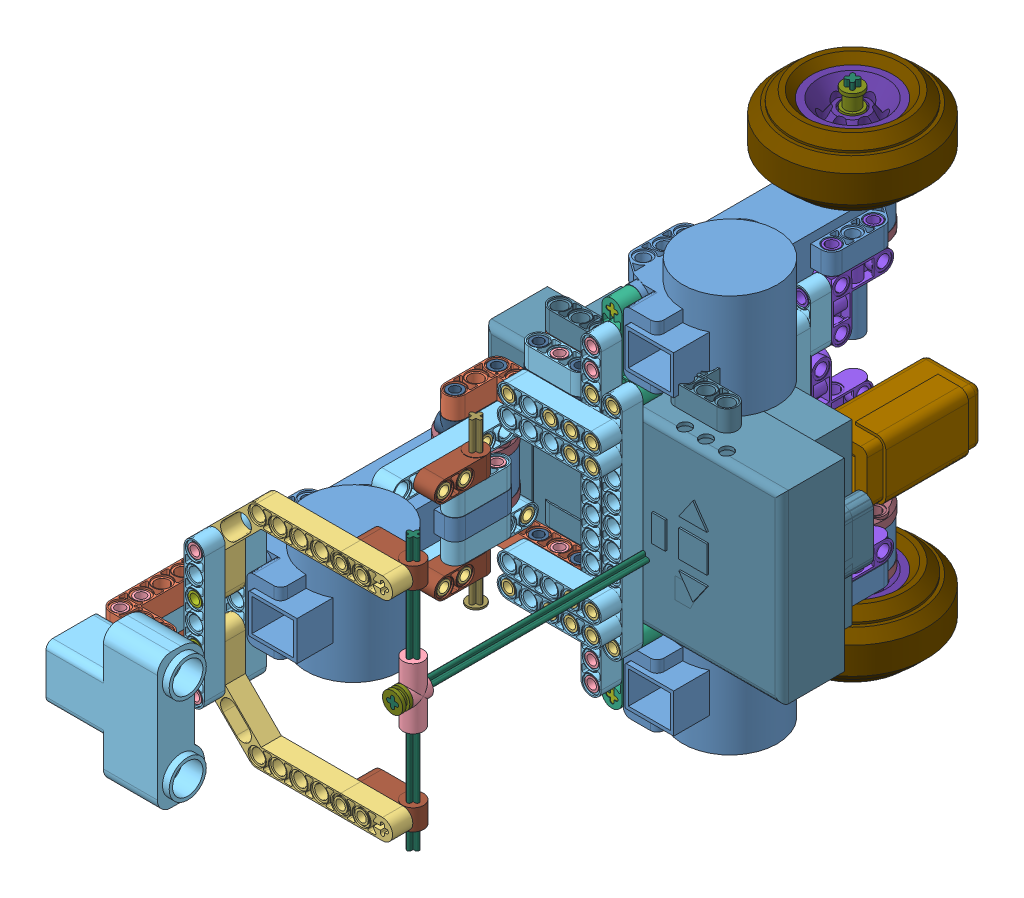
SolidWorks assembly ETRobocon2013_import, configuration Default. Lengths in mm.
Overall size (189.46 186.94 314.84).
140 component instances, 23 part files, 8 mates.
Components (placement in the parent):
- NXT+^ETRobocon2013_import-1: NXT+^ETRobocon2013_import [Default] at (300.3789 -80.9933 -218.1999) x (1 0 0) z (0 0 1) size (114.94 149.61 157.1) (virtual)
  - Motor-1: Motor [Default] at (-38.073 -89.9097 15.5114) x (0 0 1) z (1 0 0) size (103.9 39.37 46.48)
  - Motor-2: Motor [Default] at (-38.073 20.3263 15.5114) x (0 0 1) z (1 0 0) size (103.9 39.37 46.48)
  - left_connector-1: left_connector [Default] at (-38.073 -66.5417 23.3854) x (0 1 0) z (1 0 0) size (23.11 39.12 23.37)
    - L_Three_Five_90degrees-1: L_Three_Five_90degrees [Default] x (0 1 0) z (-1 0 0) size (39.12 23.37 7.87)
    - BlackConnectorSmall-1: BlackConnectorSmall [Default] at (-7.366 7.874 0) size (15.24 5.59 5.59)
    - BlackConnectorSmall-2: BlackConnectorSmall [Default] at (-15.24 -23.622 0) size (15.24 5.59 5.59)
    - BlueConnectorLong-1: BlueConnectorLong [Default] at (-15.24 -7.874 0) size (22.86 5.59 5.59)
  - right_connector-1: right_connector [Default] at (-38.073 12.1983 23.3854) x (0 1 0) z (1 0 0) size (23.11 39.12 23.37)
    - L_Three_Five_90degrees-1: L_Three_Five_90degrees [Default] x (0 1 0) z (-1 0 0) size (39.12 23.37 7.87)
    - BlackConnectorSmall-1: BlackConnectorSmall [Default] at (0 7.874 0) x (-1 0 0) z (0 0 -1) size (15.24 5.59 5.59)
    - BlackConnectorSmall-2: BlackConnectorSmall [Default] at (7.874 -23.622 0) x (-1 0 0) z (0 0 -1) size (15.24 5.59 5.59)
    - BlueConnectorLong-1: BlueConnectorLong [Default] at (7.874 -7.874 0) x (-1 0 0) z (0 0 -1) size (22.86 5.59 5.59)
  - horizontal_connector-1: horizontal_connector [Default] at (-22.325 -30.8547 35.1964) x (0 1 0) z (1 0 0) size (133.6 31.24 39.12)
    - All_Straight-1: All_Straight [Eleven] at (31.496 0 0) x (1 0 0) z (0 1 0) size (86.36 7.62 7.87)
    - BlackConnectorSmall-1: BlackConnectorSmall [Default] at (39.37 7.62 0) x (0 -1 0) z (0 0 1) size (15.24 5.59 5.59)
    - BlackConnectorSmall-2: BlackConnectorSmall [Default] at (-39.37 7.62 0) x (0 -1 0) z (0 0 1) size (15.24 5.59 5.59)
    - BlackConnectorSmall-4: BlackConnectorSmall [Default] at (-23.622 0.254 0) x (0 1 0) z (0 0 -1) size (15.24 5.59 5.59)
    - BlackConnectorSmall-5: BlackConnectorSmall [Default] at (23.622 0.254 0) x (0 1 0) z (0 0 -1) size (15.24 5.59 5.59)
    - L_Two_Four_90degrees-1: L_Two_Four_90degrees [Default] at (47.4776 -6.6697 -16.0899) x (1 0 0) z (0 -1 0) size (31.24 15.49 7.87)
    - L_Two_Four_90degrees-3: L_Two_Four_90degrees [Default] at (-47.4776 -1.2043 -16.0899) x (-1 0 0) z (0 1 0) size (31.24 15.49 7.87)
    - BlackConnectorSmall-6: BlackConnectorSmall [Default] at (-39.37 -7.62 -7.874) x (0 1 0) z (0 0 -1) size (15.24 5.59 5.59)
    - BlackConnectorSmall-7: BlackConnectorSmall [Default] at (39.37 -7.62 -7.874) x (0 1 0) z (0 0 -1) size (15.24 5.59 5.59)
    - BlueConnectorLong-1: BlueConnectorLong [Default] at (47.244 7.62 -7.874) x (0 -1 0) z (-1 0 0) size (22.86 5.59 5.59)
    - BlueConnectorLong-2: BlueConnectorLong [Default] at (55.118 7.62 -7.874) x (0 -1 0) z (-1 0 0) size (22.86 5.59 5.59)
    - BlueConnectorLong-3: BlueConnectorLong [Default] at (-47.244 7.62 -7.874) x (0 -1 0) z (0 0 1) size (22.86 5.59 5.59)
    - BlueConnectorLong-4: BlueConnectorLong [Default] at (-55.118 7.62 -7.874) x (0 -1 0) z (0 0 1) size (22.86 5.59 5.59)
    - All_Straight-3: All_Straight [Fifteen] at (47.244 0 -7.874) x (1 0 0) z (0 1 0) size (117.86 7.62 7.87)
    - BlackConnectorSmall-8: BlackConnectorSmall [Default] at (23.622 0.254 -7.874) x (0 1 0) z (0 0 -1) size (15.24 5.59 5.59)
    - BlackConnectorSmall-9: BlackConnectorSmall [Default] at (-23.622 0.254 -7.874) x (0 1 0) z (0 0 -1) size (15.24 5.59 5.59)
    - All_Straight-4: All_Straight [Five] at (-23.622 15.748 -7.874) x (0 0 1) z (0 -1 0) size (39.12 7.62 7.87)
    - All_Straight-5: All_Straight [Five] at (23.622 15.748 -7.874) x (0 0 1) z (0 -1 0) size (39.12 7.62 7.87)
    - BlueConnectorCross_Tube-1: BlueConnectorCross_Tube [Default] at (62.992 -7.874 -7.874) x (0 -1 0) z (0 0 1) size (15.24 5.08 5.08)
    - BlueConnectorCross_Tube-2: BlueConnectorCross_Tube [Default] at (-62.992 -7.874 -7.874) x (0 -1 0) z (0 0 -1) size (15.24 5.08 5.08)
  - lower_horizontal_connector-1: lower_horizontal_connector [Default] at (-14.451 0.6413 -19.9216) x (0 1 0) z (1 0 0) size (117.86 51.45 29.62)
    - All_Straight-1: All_Straight [Eleven] x (1 0 0) z (0 1 0) size (86.36 7.62 7.87)
    - BlueConnectorLong-1: BlueConnectorLong [Default] at (7.874 7.493 0) x (0 -1 0) z (0 0 1) size (22.86 5.59 5.59)
    - BlueConnectorLong-2: BlueConnectorLong [Default] at (-70.866 7.493 0) x (0 -1 0) z (0 0 1) size (22.86 5.59 5.59)
    - All_Straight-2: All_Straight [Three] at (7.874 -8.001 0) x (1 0 0) z (0 1 0) size (23.37 7.62 7.87)
    - All_Straight-3: All_Straight [Three] at (-70.866 -8.001 0) x (1 0 0) z (0 1 0) size (23.37 7.62 7.87)
    - Light_Gray_X10-1: Light_Gray_X10 [Default] at (-70.866 -15.621 0) size (31.24 31.24 7.62)
    - Light_Gray_X10-3: Light_Gray_X10 [Default] at (7.874 -15.621 0) x (-1 0 0) z (0 0 -1) size (31.24 31.24 7.62)
    - Light_Gray_X10-4: Light_Gray_X10 [Default] at (-15.748 -8.001 0) size (31.24 31.24 7.62)
    - Light_sensor-1: Light_sensor [Default] at (-31.904 -21.981 14.31) x (-1 0 0) z (0 -1 0) size (22.5 29.62 43.2)
  - left_rider_bottom-1: left_rider_bottom [Default] at (-65.632 -46.6027 78.5034) x (0 1 0) z (1 0 0) size (39.12 54.99 54.99)
    - All_Straight-1: All_Straight [Seven] x (0 1 0) z (0 0 1) size (54.86 7.62 7.87)
    - BlackConnectorSmall-1: BlackConnectorSmall [Default] at (0 0 15.494) x (0 0 -1) z (1 0 0) size (15.24 5.59 5.59)
    - BlackConnectorSmall-3: BlackConnectorSmall [Default] at (0 -7.874 15.494) x (0 0 -1) z (1 0 0) size (15.24 5.59 5.59)
    - BlackConnectorSmall-4: BlackConnectorSmall [Default] at (0 -23.622 -7.62) x (0 0 1) z (1 0 0) size (15.24 5.59 5.59)
    - BlackConnectorSmall-5: BlackConnectorSmall [Default] at (0 -39.37 -7.62) x (0 0 1) z (1 0 0) size (15.24 5.59 5.59)
    - Light_Gray_X1-1: Light_Gray_X1 [Default] at (3.937 -31.496 -3.937) x (0 1 0) z (0 0 1) size (23.62 23.11 7.87)
    - StraightTurn_Twohole_1Cross-1: StraightTurn_Twohole_1Cross [Default] at (3.81 -7.747 11.811) x (0 -1 0) z (-1 0 0) size (23.5 7.87 7.87)
    - L_Three_Five_90degrees-1: L_Three_Five_90degrees [Default] at (-11.557 -39.37 3.937) x (0 0 -1) z (1 0 0) size (39.12 23.37 7.87)
    - Light_Gray_X1-2: Light_Gray_X1 [Default] at (-19.685 -39.37 19.685) x (0 0 -1) z (0 -1 0) size (23.62 23.11 7.87)
    - BlueConnectorLong-1: BlueConnectorLong [Default] at (-27.305 -39.37 19.685) size (22.86 5.59 5.59)
    - BlackConnectorSmall-6: BlackConnectorSmall [Default] at (-15.748 -27.813 11.811) x (0 -1 0) z (0 0 1) size (15.24 5.59 5.59)
    - BlackConnectorSmall-7: BlackConnectorSmall [Default] at (-15.748 -27.813 27.559) x (0 -1 0) z (0 0 1) size (15.24 5.59 5.59)
    - All_Straight-2: All_Straight [Five] at (-15.748 -35.433 19.685) x (0 0 -1) z (0 1 0) size (39.12 7.62 7.87)
    - All_Straight-3: All_Straight [Three] at (-27.559 -39.37 19.685) x (0 0 -1) z (1 0 0) size (23.37 7.62 7.87)
    - BlackConnectorSmall-8: BlackConnectorSmall [Default] at (-15.748 -43.053 35.433) x (0 1 0) z (0 0 1) size (15.24 5.59 5.59)
    - BlackConnectorSmall-9: BlackConnectorSmall [Default] at (-15.748 -43.053 43.307) x (0 1 0) z (1 0 0) size (15.24 5.59 5.59)
  - right_rider_bottom-1: right_rider_bottom [Default] at (-65.632 -15.1067 78.5034) x (0 1 0) z (1 0 0) size (39.12 54.99 54.99)
    - All_Straight-1: All_Straight [Seven] x (0 1 0) z (0 0 1) size (54.86 7.62 7.87)
    - BlackConnectorSmall-1: BlackConnectorSmall [Default] at (0 0 15.494) x (0 0 -1) z (1 0 0) size (15.24 5.59 5.59)
    - BlackConnectorSmall-3: BlackConnectorSmall [Default] at (0 -7.874 15.494) x (0 0 -1) z (1 0 0) size (15.24 5.59 5.59)
    - BlackConnectorSmall-4: BlackConnectorSmall [Default] at (0 -23.622 -7.62) x (0 0 1) z (1 0 0) size (15.24 5.59 5.59)
    - BlackConnectorSmall-5: BlackConnectorSmall [Default] at (0 -39.37 -7.62) x (0 0 1) z (1 0 0) size (15.24 5.59 5.59)
    - Light_Gray_X1-1: Light_Gray_X1 [Default] at (3.937 -31.496 -3.937) x (0 1 0) z (0 0 1) size (23.62 23.11 7.87)
    - StraightTurn_Twohole_1Cross-1: StraightTurn_Twohole_1Cross [Default] at (3.81 -7.747 11.811) x (0 -1 0) z (-1 0 0) size (23.5 7.87 7.87)
    - L_Three_Five_90degrees-1: L_Three_Five_90degrees [Default] at (4.191 -39.37 3.937) x (0 0 -1) z (1 0 0) size (39.12 23.37 7.87)
    - Light_Gray_X1-2: Light_Gray_X1 [Default] at (19.685 -39.37 19.685) x (0 0 -1) z (0 1 0) size (23.62 23.11 7.87)
    - BlueConnectorLong-1: BlueConnectorLong [Default] at (27.305 -39.37 19.685) x (-1 0 0) z (0 0 -1) size (22.86 5.59 5.59)
    - BlackConnectorSmall-6: BlackConnectorSmall [Default] at (15.748 -27.813 11.811) x (0 -1 0) z (0 0 1) size (15.24 5.59 5.59)
    - BlackConnectorSmall-7: BlackConnectorSmall [Default] at (15.748 -27.813 27.559) x (0 -1 0) z (0 0 1) size (15.24 5.59 5.59)
    - All_Straight-2: All_Straight [Five] at (15.748 -35.433 19.685) x (0 0 -1) z (0 1 0) size (39.12 7.62 7.87)
    - All_Straight-3: All_Straight [Three] at (27.559 -39.37 19.685) x (0 0 -1) z (-1 0 0) size (23.37 7.62 7.87)
    - BlackConnectorSmall-8: BlackConnectorSmall [Default] at (15.748 -27.813 43.307) x (0 -1 0) z (0 0 1) size (15.24 5.59 5.59)
    - BlackConnectorSmall-9: BlackConnectorSmall [Default] at (15.748 -27.813 35.433) x (0 -1 0) z (0 0 1) size (15.24 5.59 5.59)
  - CrossTemplateWithCap-1: CrossTemplateWithCap [Eight] at (-53.821 -61.3347 64.2794) x (0 0 -1) z (0 1 0) size (6.6 6.6 60.96)
  - Rotor-1: Rotor [Default] at (-69.569 -23.6157 47.0074) x (0 0 -1) z (0 1 0) size (23.62 23.62 23.66)
  - CPU-1: CPU [Default] at (0 15.748 0) size (111.76 85.98 40)
- WheelLeft^ETRobocon2013_import-1: WheelLeft^ETRobocon2013_import [Default] at (270.1799 -49.491 -273.5545) x (-0.695581 0 -0.718448) z (0 1 0) size (55.88 55.88 82.68) (virtual)
  - Rotor-1: Rotor [Default] at origin size (23.62 23.62 23.66)
  - wheel_and_axle-1: wheel_and_axle [Default] at (-1.524 0 31.115) x (0 0 -1) z (-1 0 0) size (82.68 55.88 55.88)
    - CrossTemplate-1: CrossTemplate [Nine] x (0 0 -1) z (1 0 0) size (4.57 4.57 70.87)
    - Light_Gray_X8__Template-1: Light_Gray_X8__Template [one] at (2.54 0 6.35) x (0 0 -1) z (1 0 0) size (7.62 7.62 7.87)
    - Light_Gray_X12-1: Light_Gray_X12 [Rim] at (16.637 0 -9.144) x (0 0 1) z (-1 0 0) size (30.48 30.48 20.07)
    - Light_Gray_X13-1: Light_Gray_X13 [Tire] at (16.637 0 6.096) x (0 0 -1) z (1 0 0) size (55.88 55.88 25.4)
    - Light_Gray_X8__Template-2: Light_Gray_X8__Template [half] at (22.86 0 6.35) x (0 0 -1) z (1 0 0) size (7.62 7.62 3.94)
    - CrossComplementEnd_Small-1: CrossComplementEnd_Small [Three] at (59.054 0 0) x (0 0 -1) z (1 0 0) size (7.62 7.62 23.62)
- WheelRight^ETRobocon2013_import-1: WheelRight^ETRobocon2013_import [Default] at (270.1799 -159.727 -273.5545) x (-0.059852 0 -0.998207) z (0 1 0) size (55.88 55.88 82.68) (virtual)
  - Rotor-1: Rotor [Default] at origin size (23.62 23.62 23.66)
  - wheel_and_axle-1: wheel_and_axle [Default] at (-1.524 0 -45.593) x (0 0 1) z (-1 0 0) size (82.68 55.88 55.88)
    - CrossTemplate-1: CrossTemplate [Nine] x (0 0 -1) z (1 0 0) size (4.57 4.57 70.87)
    - Light_Gray_X8__Template-1: Light_Gray_X8__Template [one] at (2.54 0 6.35) x (0 0 -1) z (1 0 0) size (7.62 7.62 7.87)
    - Light_Gray_X12-1: Light_Gray_X12 [Rim] at (16.637 0 -9.144) x (0 0 1) z (-1 0 0) size (30.48 30.48 20.07)
    - Light_Gray_X13-1: Light_Gray_X13 [Tire] at (16.637 0 6.096) x (0 0 -1) z (1 0 0) size (55.88 55.88 25.4)
    - Light_Gray_X8__Template-2: Light_Gray_X8__Template [half] at (22.86 0 6.35) x (0 0 -1) z (1 0 0) size (7.62 7.62 3.94)
    - CrossComplementEnd_Small-1: CrossComplementEnd_Small [Three] at (59.054 0 0) x (0 0 -1) z (1 0 0) size (7.62 7.62 23.62)
- Humanoid^ETRobocon2013_import-1: Humanoid^ETRobocon2013_import [Default] at (213.4588 -175.874 209.2441) x (0.467807 0 -0.883831) z (0.883831 0 0.467807) size (169.56 102.11 124.61) (virtual)
  - Motor-1: Motor [Default] at (278.0414 60.089 -136.4432) x (-0.883831 0 0.467807) z (0.467807 0 0.883831) size (103.9 39.37 46.48)
  - All_Straight-1: All_Straight [Three] at (337.807 52.215 -141.3499) x (0.883831 0 -0.467807) z (0 1 0) size (23.37 7.62 7.87)
  - BlueConnectorLong-1: BlueConnectorLong [Default] at (330.8477 52.469 -137.6664) x (0 1 0) z (0 0 1) size (22.86 5.59 5.59)
  - BlueConnectorLong-2: BlueConnectorLong [Default] at (344.7662 75.583 -145.0334) x (0 -1 0) z (-0.122872 0 0.992423) size (22.86 5.59 5.59)
  - All_Straight-2: All_Straight [Three] at (337.807 67.963 -141.3499) x (-0.883831 0 0.467807) z (0 1 0) size (23.37 7.62 7.87)
  - CrossConnectorLong-1: CrossConnectorLong [Default] at (271.9809 44.341 -131.4163) x (0.769691 0 -0.638416) z (0 1 0) size (7.62 7.62 23.62)
  - CrossConnectorLong-2: CrossConnectorLong [Default] at (285.8995 44.341 -138.7833) x (0.769691 0 -0.638416) z (0 1 0) size (7.62 7.62 23.62)
  - arms_and_chest-1: arms_and_chest [Default] at (250.6327 79.774 -113.0269) x (0 1 0) z (0.467807 0 0.883831) size (102.11 106.17 70.74)
    - All_Straight-1: All_Straight [Seven] x (1 0 0) z (0 -1 0) size (54.86 7.62 7.87)
    - BlueConnectorLong-1: BlueConnectorLong [Default] at (-39.37 -0.254 0) x (0 -1 0) z (0 0 1) size (22.86 5.59 5.59)
    - BlueConnectorLong-3: BlueConnectorLong [Default] at (7.874 -0.254 0) x (0 -1 0) z (0 0 1) size (22.86 5.59 5.59)
    - BlueConnectorCross_Tube-1: BlueConnectorCross_Tube [Default] at (-23.622 -7.874 0) x (0 1 0) z (0 0 1) size (15.24 5.08 5.08)
    - BlueConnectorCross_Tube-2: BlueConnectorCross_Tube [Default] at (-7.874 -7.874 0) x (0 1 0) z (0 0 1) size (15.24 5.08 5.08)
    - Three_Four_Seven_90degreesTurn-1: Three_Four_Seven_90degreesTurn [Default] at (-31.496 -15.494 0) x (1 0 0) z (0 1 0) size (39.12 70.61 7.62)
    - Three_Four_Seven_90degreesTurn-4: Three_Four_Seven_90degreesTurn [Default] at (0 -7.874 0) x (-1 0 0) z (0 -1 0) size (39.12 70.61 7.62)
    - All_Straight-2: All_Straight [Seven] at (0 -23.368 0) x (1 0 0) z (0 1 0) size (54.86 7.62 7.87)
    - BlackConnectorSmall-1: BlackConnectorSmall [Default] at (23.622 -7.874 47.244) x (0 -1 0) z (0 0 1) size (15.24 5.59 5.59)
    - BlackConnectorSmall-2: BlackConnectorSmall [Default] at (23.622 -7.874 55.118) x (0 -1 0) z (0 0 1) size (15.24 5.59 5.59)
    - BlackConnectorSmall-3: BlackConnectorSmall [Default] at (-55.118 -7.874 47.244) x (0 -1 0) z (0 0 1) size (15.24 5.59 5.59)
    - BlackConnectorSmall-4: BlackConnectorSmall [Default] at (-55.118 -7.874 55.118) x (0 -1 0) z (0 0 1) size (15.24 5.59 5.59)
    - BlackConnectorSmall-5: BlackConnectorSmall [Default] at (-31.496 -23.114 0) x (0 1 0) z (0 0 1) size (15.24 5.59 5.59)
    - BlackConnectorSmall-6: BlackConnectorSmall [Default] at (0 -23.114 0) x (0 1 0) z (0 0 1) size (15.24 5.59 5.59)
    - StraightTurn_Twohole_1Cross-1: StraightTurn_Twohole_1Cross [Default] at (27.432 -19.431 54.991) x (0 0 1) z (-1 0 0) size (23.5 7.87 7.87)
    - StraightTurn_Twohole_1Cross-2: StraightTurn_Twohole_1Cross [Default] at (-51.308 -19.431 54.991) x (0 0 1) z (-1 0 0) size (23.5 7.87 7.87)
    - CrossTemplate-1: CrossTemplate [Six] at (-11.938 -19.431 64.516) x (0 0 -1) z (1 0 0) size (4.57 4.57 47.24)
    - Cross_AngleHole-1: Cross_AngleHole [Default] at (-4.318 -19.431 61.468) x (0 0 1) z (-1 0 0) size (7.62 7.62 22.86)
    - CrossTemplate-2: CrossTemplate [Six] at (-66.802 -19.431 64.516) x (0 0 -1) z (1 0 0) size (4.57 4.57 47.24)
    - CrossTemplate-3: CrossTemplate [Twelve] at (-17.272 -11.684 62.992) x (1 0 0) z (0 -1 0) size (4.57 4.57 94.49)
    - Light_Gray_X8__Template-1: Light_Gray_X8__Template [half] at (-23.622 -11.684 62.992) x (1 0 0) z (0 -1 0) size (7.62 7.62 3.94)
    - BlackConnectorSmall-7: BlackConnectorSmall [Default] at (-7.874 -15.748 0) x (0 -1 0) z (0 0 1) size (15.24 5.59 5.59)
    - BlackConnectorSmall-8: BlackConnectorSmall [Default] at (-23.622 -15.748 0) x (0 -1 0) z (0 0 1) size (15.24 5.59 5.59)
  - head-1: head [Default] at (237.5152 63.2753 -95.1876) x (0.467807 0 0.883831) z (0 -1 0) size (44.45 98.81 50.8)
    - ProximitySensor-1: ProximitySensor [Default] x (1 0 0) z (0 1 0) size (44.45 50.8 27.94)
    - BlueConnectorLong-3: BlueConnectorLong [Default] at (-17.5045 0 10.8063) x (0 0 -1) z (0 -1 0) size (22.86 5.59 5.59)
    - BlueConnectorLong-4: BlueConnectorLong [Default] at (-1.7565 0 -12.3077) x (0 0 1) z (1 0 0) size (22.86 5.59 5.59)
    - L_Three_Five_90degrees-1: L_Three_Five_90degrees [Default] at (-17.5045 -7.874 10.8063) x (0 1 0) z (0 0 -1) size (39.12 23.37 7.87)
    - L_Three_Five_90degrees-3: L_Three_Five_90degrees [Default] at (-17.5045 -7.874 -4.9417) x (0 1 0) z (0 0 -1) size (39.12 23.37 7.87)
    - BlueConnectorLong-5: BlueConnectorLong [Default] at (-17.5045 -7.874 10.8063) x (0 0 -1) z (1 0 0) size (22.86 5.59 5.59)
    - BlueConnectorLong-6: BlueConnectorLong [Default] at (-17.5045 -31.496 -12.3077) x (0 0 1) z (0 -1 0) size (22.86 5.59 5.59)
    - All_Straight-2: All_Straight [Nine] at (-17.5045 -15.748 -4.6877) x (0 1 0) z (0 0 1) size (70.61 7.62 7.87)
Mates (geometry in assembly coordinates):
- Concentric28: concentric: cylinder of ? through (154.384 34.798 27.686) axis (0 1 0) radius 2.286; circle of ?
- Concentric29: concentric: cylinder of NXT+^ETRobocon2013_import-1/Rotor-1 through (230.8099 -122.6243 -171.1925) axis (0 1 0) radius 3.81; cylinder of ? through (230.8099 -100.037 -171.1925) axis (0 -1 0) radius 4.0005
- Concentric30: concentric anti-aligned: cylinder of NXT+^ETRobocon2013_import-1/Motor-2 through (270.1799 -44.919 -273.5545) axis (0 -1 0) radius 4.0005; cylinder of WheelLeft^ETRobocon2013_import-1/Rotor-1 through (270.1799 -67.5063 -273.5545) axis (0 1 0) radius 3.81
- Concentric31: concentric anti-aligned: cylinder of NXT+^ETRobocon2013_import-1/Motor-1 through (270.1799 -155.155 -273.5545) axis (0 -1 0) radius 4.0005; cylinder of WheelRight^ETRobocon2013_import-1/Rotor-1 through (270.1799 -177.7423 -273.5545) axis (0 1 0) radius 3.81
- Coincident1: coincident: plane of NXT+^ETRobocon2013_import-1/Rotor-1 through (230.8099 -119.087 -171.1925) normal (0 1 0); plane of ? through (191.9572 -119.087 -146.4609) normal (0 -1 0)
- Coincident2: coincident anti-aligned: plane of NXT+^ETRobocon2013_import-1/Motor-1 through (273.8629 -174.205 -227.6457) normal (0 -1 0); plane of WheelRight^ETRobocon2013_import-1/Rotor-1 through (270.1799 -174.205 -273.5545) normal (0 1 0)
- Coincident3: coincident anti-aligned: plane of NXT+^ETRobocon2013_import-1/Motor-2 through (273.8629 -63.969 -227.6457) normal (0 -1 0); plane of WheelLeft^ETRobocon2013_import-1/Rotor-1 through (270.1799 -63.969 -273.5545) normal (0 1 0)
- Parallel1: parallel aligned: plane of NXT+^ETRobocon2013_import-1/CPU-1 through (333.9339 -77.05 -51.4722) normal (1 0 0); plane of Humanoid^ETRobocon2013_import-1/Motor-1 through (242.6209 -119.595 -170.9385) normal (1 0 0)
